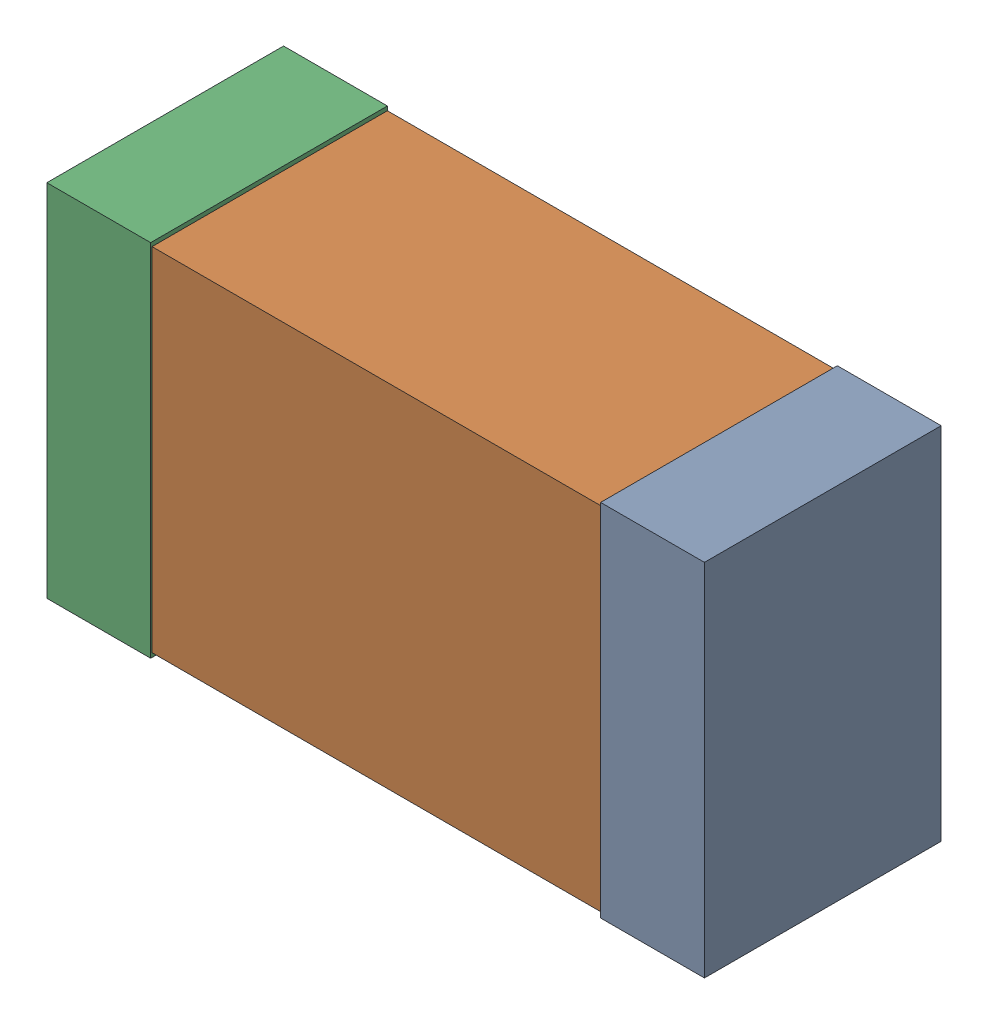
SolidWorks assembly R6Kanaloa_v2.0.0_Motor, configuration Default. Lengths in mm.
Overall size (2.38 1.3 0.85).
6 component instances, 2 part files, 0 mates.
Components (placement in the parent):
- 352877648-1: 352877648 [Default] at (55.923 114.8862 0) size (0.38 1.3 0.85)
  - Extruded_14-1: Extruded_14 [Default] at origin size (0.38 1.3 0.85)
- 352877904-1: 352877904 [Default] at (54.923 114.8862 0) size (2.2 1.27 0.85)
  - Extruded_18-1: Extruded_18 [Default] at origin size (2.2 1.27 0.85)
- 352877648-2: 352877648 [Default] at (53.923 114.8862 0) size (0.38 1.3 0.85)
  - Extruded_14-1: Extruded_14 [Default] at origin size (0.38 1.3 0.85)
